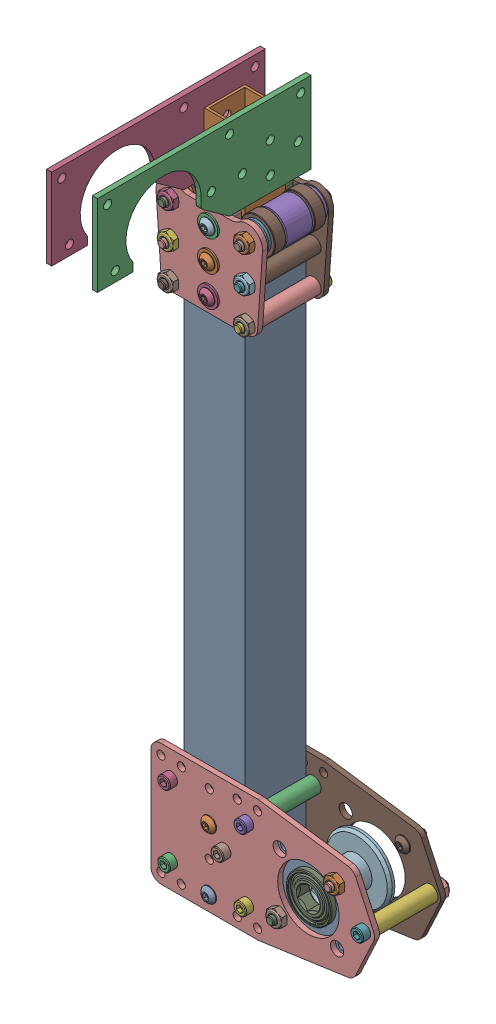
SolidWorks assembly 1 Stage Climber-In-A-Box - Custom, configuration Default. Lengths in mm.
Overall size (139.7 436.69 139.7).
7 component instances, 6 part files, 18 mates.
Components (placement in the parent):
- 1.5in Winch Kit-1: 1.5in Winch Kit [Default] at (-17.4625 0 -41.275) size (139.7 76.2 60.32)
- Stage 1 Rollers-1: Stage 1 Rollers [Default] at (108.3653 -367.9652 692.8861) x (-1 0 0) z (0 0 -1) size (69.53 61.8 55.63)
- Nylon Bearing Clamp-1: Nylon Bearing Clamp [Default] at (-70.2653 -170.752 -715.1468) size (34.04 38.1 34.04)
- Stage 1 Tube - Custom-1: Stage 1 Tube - Custom [Default] at origin size (38.1 361.95 38.1)
- 1x1 Simple Example Tube - Custom-1: 1x1 Simple Example Tube - Custom [Default] at (19.05 42.8625 -19.05) size (25.4 381 25.4)
- Hook - Custom-1: Hook - Custom [Default] at (31.75 385.8895 -44.45) x (0 0 -1) z (1 0 0) size (133.35 50.8 3.17)
- Hook - Custom-2: Hook - Custom [Default] at (3.175 385.8895 -44.45) x (0 0 -1) z (1 0 0) size (133.35 50.8 3.17)
Mates (geometry in assembly coordinates):
- Coincident2: coincident aligned: plane of Nylon Bearing Clamp-1 through (6.35 42.8625 -2.032) normal (0 -1 0); plane of 1x1 Simple Example Tube - Custom-1 through (19.05 42.8625 -19.05) normal (0 -1 0)
- Concentric4: concentric anti-aligned: cylinder of 1.5in Winch Kit-1 through (19.05 9.525 -43.8404) axis (0 0 -1) radius 2.413; cylinder of Stage 1 Tube - Custom-1 through (19.05 9.525 -38.1) axis (0 0 1) radius 2.5527
- Concentric5: concentric aligned: cylinder of 1.5in Winch Kit-1 through (28.575 38.1 39.751) axis (0 0 1) radius 2.413; cylinder of Stage 1 Tube - Custom-1 through (28.575 38.1 -38.1) axis (0 0 1) radius 2.5527
- Width2: width anti-aligned: plane of Stage 1 Tube - Custom-1 through (0 762 0) normal (0 0 1); plane of 1.5in Winch Kit-1 through (0 762 -38.1) normal (0 0 -1); plane of Stage 1 Tube - Custom-1 through (-11.1125 6.35 0) normal (0 0 -1); plane of 1.5in Winch Kit-1 through (-11.1125 6.35 -38.1) normal (0 0 1)
- Width3: width anti-aligned: plane of 1x1 Simple Example Tube - Custom-1 through (6.35 804.8625 -31.75) normal (-1 0 0); plane of Nylon Bearing Clamp-1 through (31.75 804.8625 -31.75) normal (1 0 0); plane of 1x1 Simple Example Tube - Custom-1 through (6.35 61.9125 -19.05) normal (1 0 0); plane of Nylon Bearing Clamp-1 through (31.75 61.9125 -19.05) normal (-1 0 0)
- Width4: width aligned: plane of Nylon Bearing Clamp-1 through (31.75 42.8625 -6.223) normal (-0.017452 0 -0.999848); plane of 1x1 Simple Example Tube - Custom-1 through (31.75 42.8625 -31.877) normal (-0.017452 0 0.999848); plane of Nylon Bearing Clamp-1 through (6.35 804.8625 -6.35) normal (0 0 1); plane of 1x1 Simple Example Tube - Custom-1 through (6.35 804.8625 -31.75) normal (0 0 -1)
- Width6: width anti-aligned: plane of Stage 1 Tube - Custom-1 through (1.5875 762 -1.5875) normal (1 0 0); plane of 1x1 Simple Example Tube - Custom-1 through (36.5125 762 -1.5875) normal (-1 0 0); plane of Stage 1 Tube - Custom-1 through (6.35 804.8625 -31.75) normal (-1 0 0); plane of 1x1 Simple Example Tube - Custom-1 through (31.75 804.8625 -31.75) normal (1 0 0)
- Width7: width anti-aligned: plane of Stage 1 Tube - Custom-1 through (1.5875 762 -36.5125) normal (0 0 1); plane of 1x1 Simple Example Tube - Custom-1 through (1.5875 762 -1.5875) normal (0 0 -1); plane of Stage 1 Tube - Custom-1 through (6.35 804.8625 -31.75) normal (0 0 -1); plane of 1x1 Simple Example Tube - Custom-1 through (6.35 804.8625 -6.35) normal (0 0 1)
- Concentric9: concentric anti-aligned: cylinder of 1x1 Simple Example Tube - Custom-1 through (6.35 395.4145 -19.05) axis (1 0 0) radius 2.5527; cylinder of Hook - Custom-1 through (34.925 395.4145 -19.05) axis (-1 0 0) radius 2.5527
- Coincident3: coincident anti-aligned: plane of 1x1 Simple Example Tube - Custom-1 through (31.75 804.8625 -31.75) normal (1 0 0); plane of Hook - Custom-1 through (31.75 404.9395 47.625) normal (-1 0 0)
- Parallel1: parallel aligned: plane of 1x1 Simple Example Tube - Custom-1 through (6.35 423.8625 -31.75) normal (0 1 0); plane of Hook - Custom-1 through (34.925 436.6895 -44.45) normal (0 1 0)
- Concentric11: concentric anti-aligned: cylinder of 1x1 Simple Example Tube - Custom-1 through (6.35 395.4145 -19.05) axis (1 0 0) radius 2.5527; cylinder of Hook - Custom-2 through (6.35 395.4145 -19.05) axis (-1 0 0) radius 2.5527
- Coincident4: coincident anti-aligned: plane of 1x1 Simple Example Tube - Custom-1 through (6.35 804.8625 -31.75) normal (-1 0 0); plane of Hook - Custom-2 through (6.35 404.9395 47.625) normal (1 0 0)
- Parallel2: parallel aligned: plane of 1x1 Simple Example Tube - Custom-1 through (6.35 423.8625 -31.75) normal (0 1 0); plane of Hook - Custom-2 through (6.35 436.6895 -44.45) normal (0 1 0)
- Concentric12: concentric anti-aligned: cylinder of Stage 1 Rollers-1 through (19.05 333.375 -41.275) axis (0 0 -1) radius 6.3246; cylinder of Stage 1 Tube - Custom-1 through (19.05 333.375 -38.1) axis (0 0 1) radius 2.5527
- Concentric13: concentric anti-aligned: cylinder of Stage 1 Rollers-1 through (19.05 352.425 -41.275) axis (0 0 -1) radius 6.3246; cylinder of Stage 1 Tube - Custom-1 through (19.05 352.425 -38.1) axis (0 0 1) radius 2.5527
- Width8: width anti-aligned: plane of Stage 1 Rollers-1 through (42.8135 374.65 -41.275) normal (0 0 -1); plane of Stage 1 Tube - Custom-1 through (42.8135 374.65 3.175) normal (0 0 1); plane of Stage 1 Rollers-1 through (0 762 0) normal (0 0 1); plane of Stage 1 Tube - Custom-1 through (0 762 -38.1) normal (0 0 -1)
- Width9: width: plane of assembly; plane of assembly; plane of assembly; plane of assembly; plane of Stage 1 Rollers-1 through (31.75 42.8625 -36.068) normal (0 -1 0); plane of Nylon Bearing Clamp-1 through (25.4 323.85 -38.1) normal (0 -1 0); plane of Nylon Bearing Clamp-1 through (31.75 80.9625 -36.068) normal (0 1 0)
